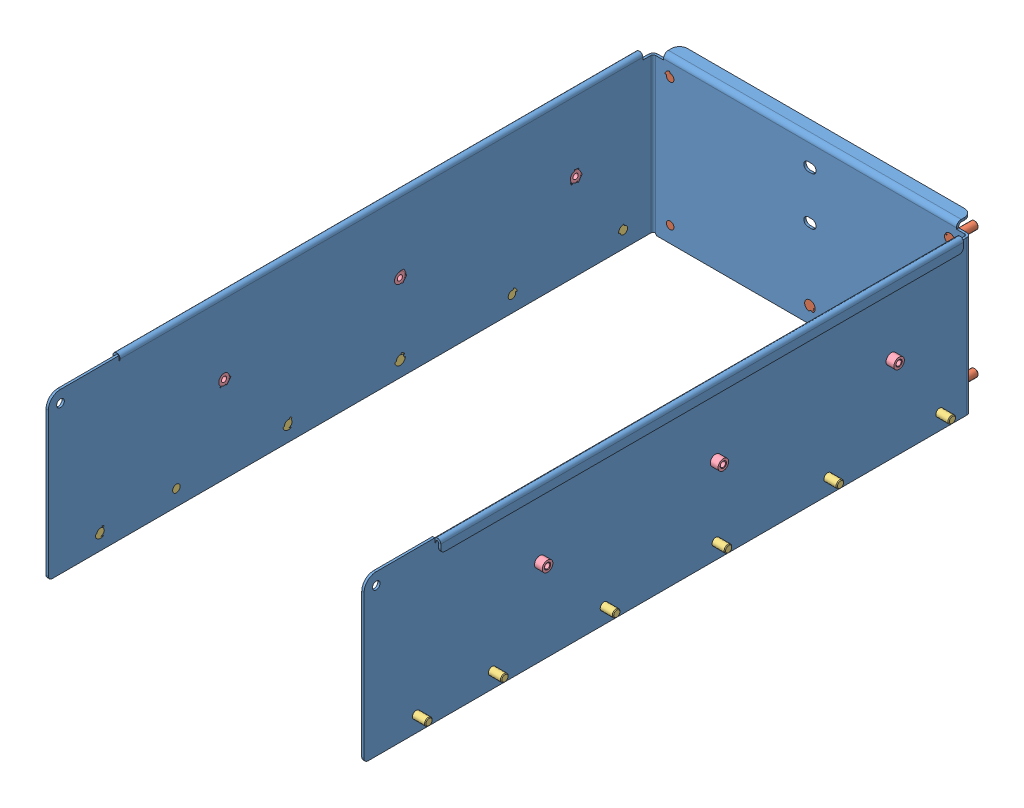
SolidWorks assembly 619012060, configuration Default. Lengths in mm.
Overall size (136.56 64.26 250.39).
24 component instances, 3 part files, 10 mates.
Components (placement in the parent):
- 619012060_01-1: 619012060_01 [open bottom] at origin size (130.24 64.26 246.74)
- flush stud_pmm-4: flush stud_pmm [PEM FH-M3-10 X] at (55.5625 5.5563 0) x (0 0 -1) z (1 0 0) size (10 4.6 4.6)
- flush stud_pmm-9: flush stud_pmm [PEM FH-M3-6 X] at (62.2808 6.35 11.684) size (6 4.6 4.6)
- flush stud_pmm-15: flush stud_pmm [PEM FH-M3-6 X] at (-62.2808 6.35 11.684) x (-1 0 0) z (0 -0.924225 -0.381849) size (6 4.6 4.6)
- thin sheet standoff_pmm-1: thin sheet standoff_pmm [PEM TSO-M25-400 ZI] at (62.2808 34.4329 30.8381) x (0 -1 0) z (0 0 1) size (4.8 4 5.54)
- thin sheet standoff_pmm-7: thin sheet standoff_pmm [PEM TSO-M25-400 ZI] at (-62.2808 34.4329 30.8381) x (0 -0.381849 0.924225) z (0 -0.924225 -0.381849) size (4.8 4 5.54)
- flush stud_pmm-5: flush stud_pmm [PEM FH-M3-10 X] at (-55.5625 5.5563 0) x (0 0 -1) z (1 0 0) size (10 4.6 4.6)
- flush stud_pmm-6: flush stud_pmm [PEM FH-M3-10 X] at (-55.5625 56.3562 0) x (0 0 -1) z (1 0 0) size (10 4.6 4.6)
- flush stud_pmm-7: flush stud_pmm [PEM FH-M3-10 X] at (0 5.5563 0) x (0 0 -1) z (1 0 0) size (10 4.6 4.6)
- flush stud_pmm-8: flush stud_pmm [PEM FH-M3-10 X] at (55.5625 56.3562 0) x (0 0 -1) z (1 0 0) size (10 4.6 4.6)
- flush stud_pmm-10: flush stud_pmm [PEM FH-M3-6 X] at (62.2808 6.35 189.484) size (6 4.6 4.6)
- flush stud_pmm-11: flush stud_pmm [PEM FH-M3-6 X] at (62.2808 6.35 100.584) size (6 4.6 4.6)
- flush stud_pmm-16: flush stud_pmm [PEM FH-M3-6 X] at (-62.2808 6.35 189.484) x (-1 0 0) z (0 -0.924225 -0.381849) size (6 4.6 4.6)
- flush stud_pmm-17: flush stud_pmm [PEM FH-M3-6 X] at (-62.2808 6.35 100.584) x (-1 0 0) z (0 -0.924225 -0.381849) size (6 4.6 4.6)
- flush stud_pmm-12: flush stud_pmm [PEM FH-M3-6 X] at (62.2808 6.35 56.134) size (6 4.6 4.6)
- flush stud_pmm-13: flush stud_pmm [PEM FH-M3-6 X] at (62.2808 6.35 145.034) size (6 4.6 4.6)
- flush stud_pmm-18: flush stud_pmm [PEM FH-M3-6 X] at (-62.2808 6.35 56.134) x (-1 0 0) z (0 -0.924225 -0.381849) size (6 4.6 4.6)
- flush stud_pmm-19: flush stud_pmm [PEM FH-M3-6 X] at (-62.2808 6.35 145.034) x (-1 0 0) z (0 -0.924225 -0.381849) size (6 4.6 4.6)
- flush stud_pmm-14: flush stud_pmm [PEM FH-M3-6 X] at (62.2808 6.35 219.6465) size (6 4.6 4.6)
- flush stud_pmm-20: flush stud_pmm [PEM FH-M3-6 X] at (-62.2808 6.35 219.6465) x (-1 0 0) z (0 -0.924225 -0.381849) size (6 4.6 4.6)
- thin sheet standoff_pmm-8: thin sheet standoff_pmm [PEM TSO-M25-400 ZI] at (-62.2808 34.4329 170.5381) x (0 -0.381849 0.924225) z (0 -0.924225 -0.381849) size (4.8 4 5.54)
- thin sheet standoff_pmm-9: thin sheet standoff_pmm [PEM TSO-M25-400 ZI] at (-62.2808 34.4329 100.6881) x (0 -0.381849 0.924225) z (0 -0.924225 -0.381849) size (4.8 4 5.54)
- thin sheet standoff_pmm-5: thin sheet standoff_pmm [PEM TSO-M25-400 ZI] at (62.2808 34.4329 170.5381) x (0 -1 0) z (0 0 1) size (4.8 4 5.54)
- thin sheet standoff_pmm-6: thin sheet standoff_pmm [PEM TSO-M25-400 ZI] at (62.2808 34.4329 100.6881) x (0 -1 0) z (0 0 1) size (4.8 4 5.54)
Mates (geometry in assembly coordinates):
- Concentric2: concentric anti-aligned: cylinder of 619012060_01-1 through (55.5625 5.5563 -0.9119) axis (0 0 -1) radius 1.5; cylinder of flush stud_pmm-4 through (55.5625 5.5563 0) axis (0 0 1) radius 1.5
- Coincident61: coincident aligned: plane of 619012060_01-1 through (-62.1538 63.5 0) normal (0 0 1); plane of flush stud_pmm-4 through (55.5625 5.5563 0) normal (0 0 1)
- Concentric3: concentric anti-aligned: cylinder of 619012060_01-1 through (63.1927 6.35 11.684) axis (1 0 0) radius 1.5; cylinder of flush stud_pmm-9 through (62.2808 6.35 11.684) axis (-1 0 0) radius 1.5
- Coincident62: coincident aligned: plane of 619012060_01-1 through (62.2808 0 0) normal (-1 0 0); plane of flush stud_pmm-9 through (62.2808 6.35 11.684) normal (-1 0 0)
- Concentric4: concentric aligned: cylinder of 619012060_01-1 through (63.1927 6.35 11.684) axis (1 0 0) radius 1.5; cylinder of flush stud_pmm-15 through (-62.2808 6.35 11.684) axis (1 0 0) radius 1.5
- Coincident63: coincident aligned: plane of 619012060_01-1 through (-62.2808 0 0) normal (1 0 0); plane of flush stud_pmm-15 through (-62.2808 6.35 11.684) normal (1 0 0)
- Concentric5: concentric anti-aligned: cylinder of thin sheet standoff_pmm-1 through (62.2808 34.4329 30.8381) axis (-1 0 0) radius 2.095; cylinder of 619012060_01-1 through (63.1927 34.4329 30.8381) axis (1 0 0) radius 2.11
- Coincident64: coincident aligned: plane of 619012060_01-1 through (62.2808 0 0) normal (-1 0 0); plane of thin sheet standoff_pmm-1 through (62.2808 32.3379 30.8381) normal (-1 0 0)
- Concentric6: concentric aligned: cylinder of thin sheet standoff_pmm-7 through (-62.2808 34.4329 30.8381) axis (1 0 0) radius 2.095; cylinder of 619012060_01-1 through (63.1927 34.4329 30.8381) axis (1 0 0) radius 2.11
- Coincident65: coincident aligned: plane of 619012060_01-1 through (-62.2808 0 0) normal (1 0 0); plane of thin sheet standoff_pmm-7 through (-62.2808 33.6329 32.7744) normal (1 0 0)
